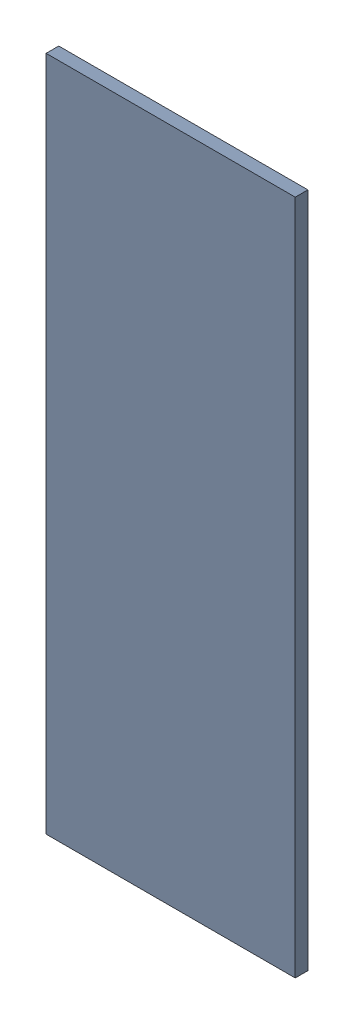
SolidWorks assembly Pad RAK4600-38(22.475mm,31.391mm) on Top Layer, configuration Predeterminado. Lengths in mm.
Overall size (0.7 1.9 0.04).
2 component instances, 1 part files, 0 mates.
Components (placement in the parent):
- Pad RAK4600-38(22.475mm,31.391mm) on Top Layer-1-1: Pad RAK4600-38(22.475mm,31.391mm) on Top Layer-1 [Predeterminado] at (-68.317 -44.187 -0.0457) size (0.7 1.9 0.04)
  - Pad RAK4600-38(22.475mm,31.391mm) on Top Layer-Part-1-1: Pad RAK4600-38(22.475mm,31.391mm) on Top Layer-Part-1 [Predeterminado] at origin size (0.7 1.9 0.04)
